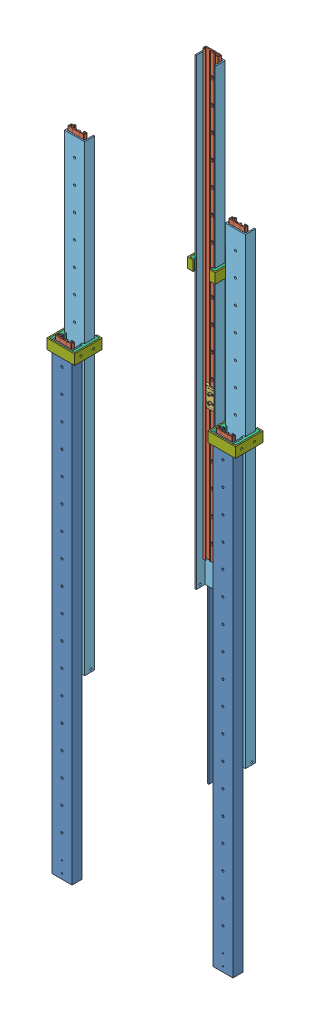
SolidWorks assembly Tower_Assem X 4, configuration Default. Lengths in mm.
Overall size (476.25 1621.22 425).
36 component instances, 7 part files, 6 mates.
Components (placement in the parent):
- Tower_Assem-1: Tower_Assem [Default] at origin size (69.85 1621.22 69.85) (flexible)
  - U-Chan_4ft_Igus-2: U-Chan_4ft_Igus [Default] at origin size (50.8 1168.4 25.4)
  - Igus_40mm_Rail-1: Igus_40mm_Rail [Default] at (25.4 61.6 -3.175) x (-1 0 0) z (0 0 -1) size (40 1117.6 8.7)
  - NW_02_40_1-1: NW_02_40_1 [Default] at (25.4 502.8196 -3.125) x (-1 0 0) z (0 0 -1) size (34 50 11.15)
  - NW_02_40_1-2: NW_02_40_1 [Default] at (25.4 584.4197 -3.125) x (-1 0 0) z (0 0 -1) size (34 50 11.15)
  - Rail_Support-1: Rail_Support [Default] at (44.45 480.1196 -12.625) x (0 0 -1) z (1 0 0) size (19.05 127 38.1)
  - U-Chan_4ft_Inside_Igus-1: U-Chan_4ft_Inside_Igus [Default] at (0 442.0196 -31.675) size (50.8 1168.4 25.4)
  - Igus_40mm_Rail-2: Igus_40mm_Rail [Default] at (25.4 503.6196 -34.85) x (-1 0 0) z (0 0 -1) size (40 1117.6 8.7)
  - NW_02_40_1-3: NW_02_40_1 [Default] at (25.4 1087.1345 -34.8) x (-1 0 0) z (0 0 -1) size (34 50 11.15)
  - Delren_Slide_Block-1: Delren_Slide_Block [Default] at (46.0375 1143 -25.4) size (11.11 25.4 63.37)
  - Delren_Slide_Block-2: Delren_Slide_Block [Default] at (4.7625 1168.4 -25.4) x (-1 0 0) z (0 0 1) size (11.11 25.4 63.37)
  - Delrin_Support-1: Delrin_Support [Default] at (-6.35 1143 0) size (69.85 25.4 69.85)
- Tower_Assem-2: Tower_Assem [Default] at (406.4 0 0) size (69.85 1621.22 69.85) (flexible)
  - U-Chan_4ft_Igus-2: U-Chan_4ft_Igus [Default] at origin size (50.8 1168.4 25.4)
  - Igus_40mm_Rail-1: Igus_40mm_Rail [Default] at (25.4 61.6 -3.175) x (-1 0 0) z (0 0 -1) size (40 1117.6 8.7)
  - NW_02_40_1-1: NW_02_40_1 [Default] at (25.4 502.8196 -3.125) x (-1 0 0) z (0 0 -1) size (34 50 11.15)
  - NW_02_40_1-2: NW_02_40_1 [Default] at (25.4 584.4197 -3.125) x (-1 0 0) z (0 0 -1) size (34 50 11.15)
  - Rail_Support-1: Rail_Support [Default] at (44.45 480.1196 -12.625) x (0 0 -1) z (1 0 0) size (19.05 127 38.1)
  - U-Chan_4ft_Inside_Igus-1: U-Chan_4ft_Inside_Igus [Default] at (0 442.0196 -31.675) size (50.8 1168.4 25.4)
  - Igus_40mm_Rail-2: Igus_40mm_Rail [Default] at (25.4 503.6196 -34.85) x (-1 0 0) z (0 0 -1) size (40 1117.6 8.7)
  - NW_02_40_1-3: NW_02_40_1 [Default] at (25.4 637.4721 -34.8) x (-1 0 0) z (0 0 -1) size (34 50 11.15)
  - Delren_Slide_Block-1: Delren_Slide_Block [Default] at (46.0375 1143 -25.4) size (11.11 25.4 63.37)
  - Delren_Slide_Block-2: Delren_Slide_Block [Default] at (4.7625 1168.4 -25.4) x (-1 0 0) z (0 0 1) size (11.11 25.4 63.37)
  - Delrin_Support-1: Delrin_Support [Default] at (-6.35 1143 0) size (69.85 25.4 69.85)
- Tower_Assem-3: Tower_Assem [Default] at (50.8 0 -418.6473) x (-1 0 0) z (0 0 -1) size (69.85 1621.22 69.85) (flexible)
  - U-Chan_4ft_Igus-2: U-Chan_4ft_Igus [Default] at origin size (50.8 1168.4 25.4)
  - Igus_40mm_Rail-1: Igus_40mm_Rail [Default] at (25.4 61.6 -3.175) x (-1 0 0) z (0 0 -1) size (40 1117.6 8.7)
  - NW_02_40_1-1: NW_02_40_1 [Default] at (25.4 502.8196 -3.125) x (-1 0 0) z (0 0 -1) size (34 50 11.15)
  - NW_02_40_1-2: NW_02_40_1 [Default] at (25.4 584.4197 -3.125) x (-1 0 0) z (0 0 -1) size (34 50 11.15)
  - Rail_Support-1: Rail_Support [Default] at (44.45 480.1196 -12.625) x (0 0 -1) z (1 0 0) size (19.05 127 38.1)
  - U-Chan_4ft_Inside_Igus-1: U-Chan_4ft_Inside_Igus [Default] at (0 442.0196 -31.675) size (50.8 1168.4 25.4)
  - Igus_40mm_Rail-2: Igus_40mm_Rail [Default] at (25.4 503.6196 -34.85) x (-1 0 0) z (0 0 -1) size (40 1117.6 8.7)
  - NW_02_40_1-3: NW_02_40_1 [Default] at (25.4 864.5611 -34.8) x (-1 0 0) z (0 0 -1) size (34 50 11.15)
  - Delren_Slide_Block-1: Delren_Slide_Block [Default] at (46.0375 1143 -25.4) size (11.11 25.4 63.37)
  - Delren_Slide_Block-2: Delren_Slide_Block [Default] at (4.7625 1168.4 -25.4) x (-1 0 0) z (0 0 1) size (11.11 25.4 63.37)
  - Delrin_Support-1: Delrin_Support [Default] at (-6.35 1143 0) size (69.85 25.4 69.85)
Mates (geometry in assembly coordinates):
- Coincident1: coincident: plane of Tower_Assem-1/U-Chan_4ft_Igus-2 through (0 0 0) normal (0 1 0); plane of assembly through (0 0 0) normal (0 1 0)
- Coincident2: coincident aligned: plane of Tower_Assem-1/U-Chan_4ft_Inside_Igus-1 through (0 1610.4196 -31.675) normal (0 1 0); plane of Tower_Assem-2/U-Chan_4ft_Inside_Igus-1 through (406.4 1610.4196 -31.675) normal (0 1 0)
- Coincident3: coincident aligned: plane of Tower_Assem-3/U-Chan_4ft_Igus-2 through (50.8 0 -418.6473) normal (0 1 0); plane of assembly through (0 0 0) normal (0 1 0)
- Parallel1: parallel aligned: plane of Tower_Assem-2/U-Chan_4ft_Igus-2 through (457.2 1168.4 0) normal (1 0 0); plane of Tower_Assem-3/U-Chan_4ft_Igus-2 through (50.8 1168.4 -418.6473) normal (1 0 0)
- Coincident4: coincident aligned: plane of Tower_Assem-1/U-Chan_4ft_Igus-2 through (0 1168.4 0) normal (-1 0 0); plane of Tower_Assem-3/U-Chan_4ft_Igus-2 through (0 1168.4 -418.6473) normal (-1 0 0)
- Coincident6: coincident aligned: plane of Tower_Assem-1/U-Chan_4ft_Inside_Igus-1 through (0 1610.4196 -31.675) normal (0 1 0); plane of Tower_Assem-3/U-Chan_4ft_Inside_Igus-1 through (50.8 1610.4196 -386.9723) normal (0 1 0)
